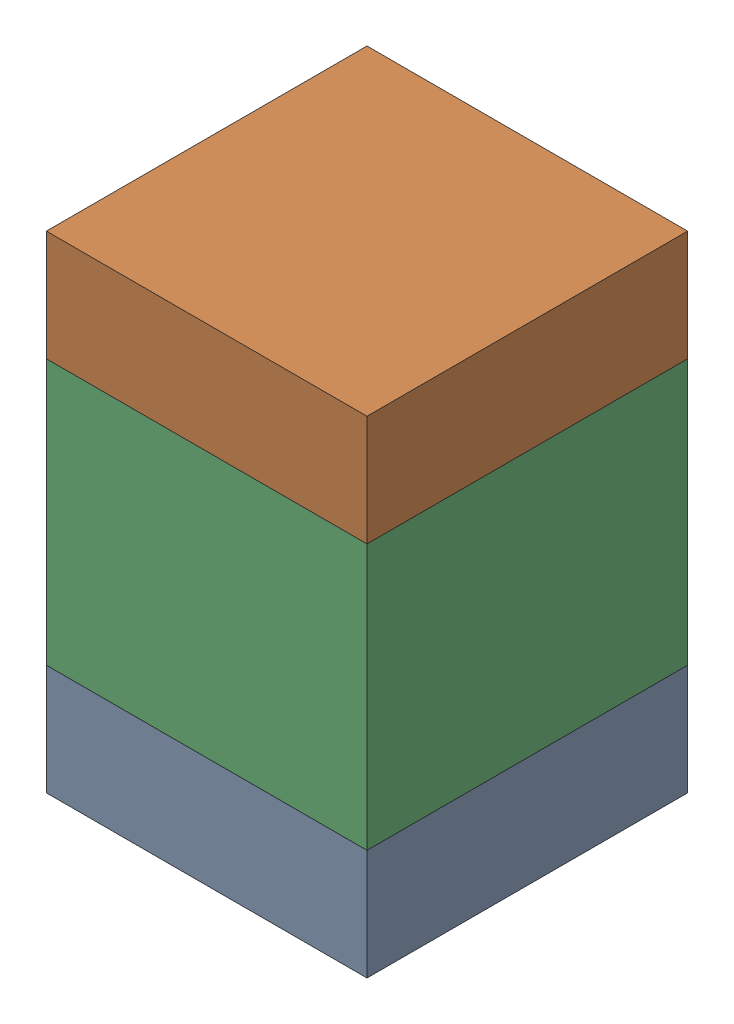
SolidWorks assembly C128_2PCB, configuration Default. Lengths in mm.
Overall size (1.45 2.2 1.45).
6 component instances, 2 part files, 0 mates.
Components (placement in the parent):
- 846485056-1: 846485056 [Default] at (104.1 99.45 0) size (1.45 0.5 1.45)
  - Extruded_39-1: Extruded_39 [Default] at origin size (1.45 0.5 1.45)
- 846485056-2: 846485056 [Default] at (104.1 101.15 0) size (1.45 0.5 1.45)
  - Extruded_39-1: Extruded_39 [Default] at origin size (1.45 0.5 1.45)
- 846485192-1: 846485192 [Default] at (104.1 100.3 0) size (1.45 1.2 1.45)
  - Extruded_40-1: Extruded_40 [Default] at origin size (1.45 1.2 1.45)
